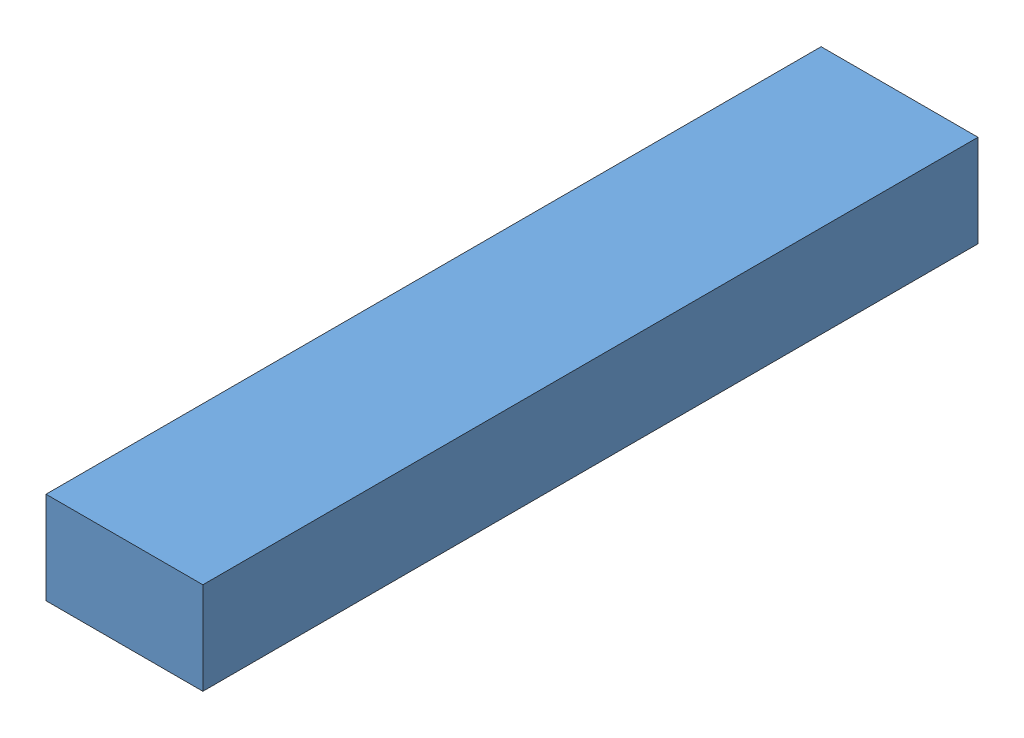
SolidWorks assembly connector, configuration Default. Lengths in mm.
Overall size (19.21 17 84).
8 component instances, 4 part files, 20 mates.
Components (placement in the parent):
- test_finger-1: test_finger [Default] at (3.0903 7.3082 4.6857) size (11.21 7 7) (hidden)
- test_footers-1: test_footers [Default] at (-5.7514 8.8587 -30.3143) size (11.88 25 84) (hidden)
- test_seat_bottom-1: test_seat_bottom [Default] at (1.6932 10.8082 -30.3143) x (0 0 1) z (-1 0 0) size (84 10 17)
- test_finger-2: test_finger [Default] at (3.0903 7.3082 -64.3143) size (11.21 7 7)
- test_finger-3: test_finger [Default] at (3.0903 7.3082 -3.3143) size (11.21 7 7)
- test_finger-4: test_finger [Default] at (3.0903 7.3082 -72.3143) size (11.21 7 7) (hidden)
- spacer_test_finger-1: spacer_test_finger [Default] at (3.0903 7.3082 3.6857) size (11.21 7 1) (hidden)
- spacer_test_finger-2: spacer_test_finger [Default] at (3.0903 7.3082 -65.3143) size (11.21 7 1) (hidden)
Mates (geometry in assembly coordinates):
- Coincident4: coincident anti-aligned: plane of test_footers-1 through (-0.3068 20.8082 11.6857) normal (1 0 0); plane of test_seat_bottom-1 through (-0.3068 20.8082 -72.3143) normal (-1 0 0)
- Coincident5: coincident aligned: plane of test_footers-1 through (-5.7514 8.8587 11.6857) normal (0 0 1); plane of test_seat_bottom-1 through (16.6932 20.8082 11.6857) normal (0 0 1)
- Coincident7: coincident anti-aligned: plane of test_finger-1 through (8.6932 10.8082 11.6857) normal (0 1 0); plane of test_seat_bottom-1 through (1.6932 10.8082 -30.3143) normal (0 -1 0)
- Coincident8: coincident anti-aligned: plane of test_finger-1 through (-0.3068 10.8082 11.6857) normal (-0.953769 0.300539 0); plane of test_footers-1 through (-0.3068 10.8082 11.6857) normal (0.953769 -0.300539 0)
- Coincident9: coincident aligned: plane of test_finger-1 through (3.0903 7.3082 11.6857) normal (0 0 1); plane of test_seat_bottom-1 through (16.6932 20.8082 11.6857) normal (0 0 1)
- Coincident10: coincident anti-aligned: plane of test_footers-1 through (-0.3068 10.8082 11.6857) normal (0.953769 -0.300539 0); plane of test_finger-4 through (-0.3068 10.8082 -65.3143) normal (-0.953769 0.300539 0)
- Coincident11: coincident anti-aligned: plane of test_seat_bottom-1 through (1.6932 10.8082 -30.3143) normal (0 -1 0); plane of test_finger-4 through (8.6932 10.8082 -65.3143) normal (0 1 0)
- Coincident12: coincident aligned: plane of test_footers-1 through (-5.7514 8.8587 -72.3143) normal (0 0 -1); plane of test_finger-4 through (3.0903 7.3082 -72.3143) normal (0 0 -1)
- Coincident14: coincident anti-aligned: plane of test_footers-1 through (-0.3068 10.8082 11.6857) normal (0.953769 -0.300539 0); plane of test_finger-2 through (-0.3068 10.8082 -57.3143) normal (-0.953769 0.300539 0)
- Coincident15: coincident anti-aligned: plane of test_seat_bottom-1 through (1.6932 10.8082 -30.3143) normal (0 -1 0); plane of test_finger-2 through (8.6932 10.8082 -57.3143) normal (0 1 0)
- Coincident16: coincident anti-aligned: plane of test_footers-1 through (-0.3068 10.8082 11.6857) normal (0.953769 -0.300539 0); plane of test_finger-3 through (-0.3068 10.8082 3.6857) normal (-0.953769 0.300539 0)
- Coincident18: coincident anti-aligned: plane of test_seat_bottom-1 through (1.6932 10.8082 -30.3143) normal (0 -1 0); plane of test_finger-3 through (8.6932 10.8082 3.6857) normal (0 1 0)
- Coincident19: coincident anti-aligned: plane of test_finger-1 through (3.0903 7.3082 4.6857) normal (0 0 -1); plane of spacer_test_finger-1 through (3.0903 7.3082 4.6857) normal (0 0 1)
- Coincident20: coincident anti-aligned: plane of test_finger-3 through (3.0903 7.3082 3.6857) normal (0 0 1); plane of spacer_test_finger-1 through (3.0903 7.3082 3.6857) normal (0 0 -1)
- Coincident21: coincident anti-aligned: plane of test_seat_bottom-1 through (1.6932 10.8082 -30.3143) normal (0 -1 0); plane of spacer_test_finger-1 through (8.6932 10.8082 4.6857) normal (0 1 0)
- Coincident22: coincident anti-aligned: plane of test_footers-1 through (-0.3068 10.8082 11.6857) normal (0.953769 -0.300539 0); plane of spacer_test_finger-1 through (-0.3068 10.8082 4.6857) normal (-0.953769 0.300539 0)
- Coincident23: coincident anti-aligned: plane of test_finger-4 through (3.0903 7.3082 -65.3143) normal (0 0 1); plane of spacer_test_finger-2 through (3.0903 7.3082 -65.3143) normal (0 0 -1)
- Coincident24: coincident anti-aligned: plane of test_finger-2 through (3.0903 7.3082 -64.3143) normal (0 0 -1); plane of spacer_test_finger-2 through (3.0903 7.3082 -64.3143) normal (0 0 1)
- Coincident25: coincident anti-aligned: plane of test_seat_bottom-1 through (1.6932 10.8082 -30.3143) normal (0 -1 0); plane of spacer_test_finger-2 through (8.6932 10.8082 -64.3143) normal (0 1 0)
- Coincident26: coincident anti-aligned: plane of test_footers-1 through (-0.3068 10.8082 11.6857) normal (0.953769 -0.300539 0); plane of spacer_test_finger-2 through (-0.3068 10.8082 -64.3143) normal (-0.953769 0.300539 0)
